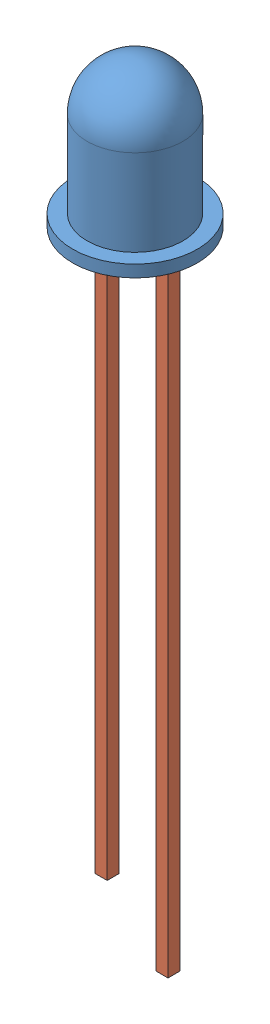
SolidWorks assembly led_full, configuration Default. Lengths in mm.
Overall size (5.2 32.34 5.2).
2 component instances, 2 part files, 0 mates.
Components (placement in the parent):
- led2-1: led2 [Default] at (-172.081 10.1513 24.3661) size (5.2 6.1 5.2)
- led-2: led [Default] at (5.5552 15.5162 24.092) size (3.04 28.26 0.5)
